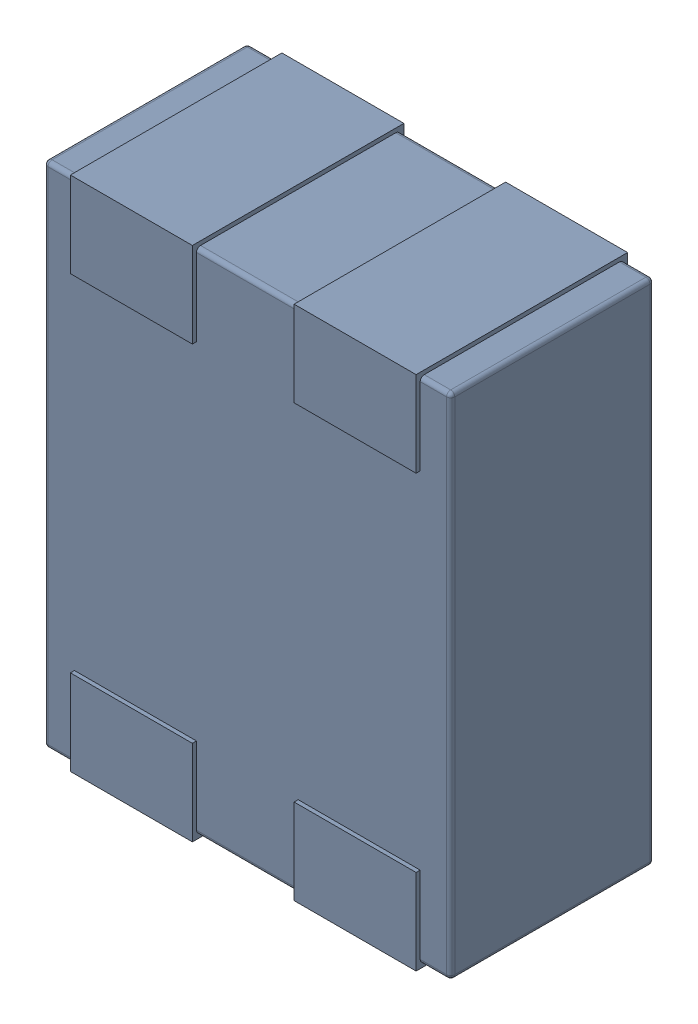
SolidWorks assembly L5, configuration Défaut. Lengths in mm.
Overall size (1 1.27 0.52).
4 component instances, 1 part files, 0 mates.
Components (placement in the parent):
- MCZ1210DH900L2TA0G-1: MCZ1210DH900L2TA0G [Défaut] at (66.3944 -33.8195 -1.6) x (-1 0 0) z (0 0 1) size (1 1.27 0.52)
  - 3D_PCB1_2021-12-30 (1).step-1: 3D_PCB1_2021-12-30 (1).step [Défaut] at origin size (1 1.27 0.52)
    - a3ec64f90eb5404ebd79eca0046a794a.step-1: a3ec64f90eb5404ebd79eca0046a794a.step [Défaut] at (5.0419 -6.8961 1.6) size (1 1.27 0.52)
      - SOLID.step_650-1: SOLID.step_650 [Défaut] at origin size (1 1.27 0.52)
